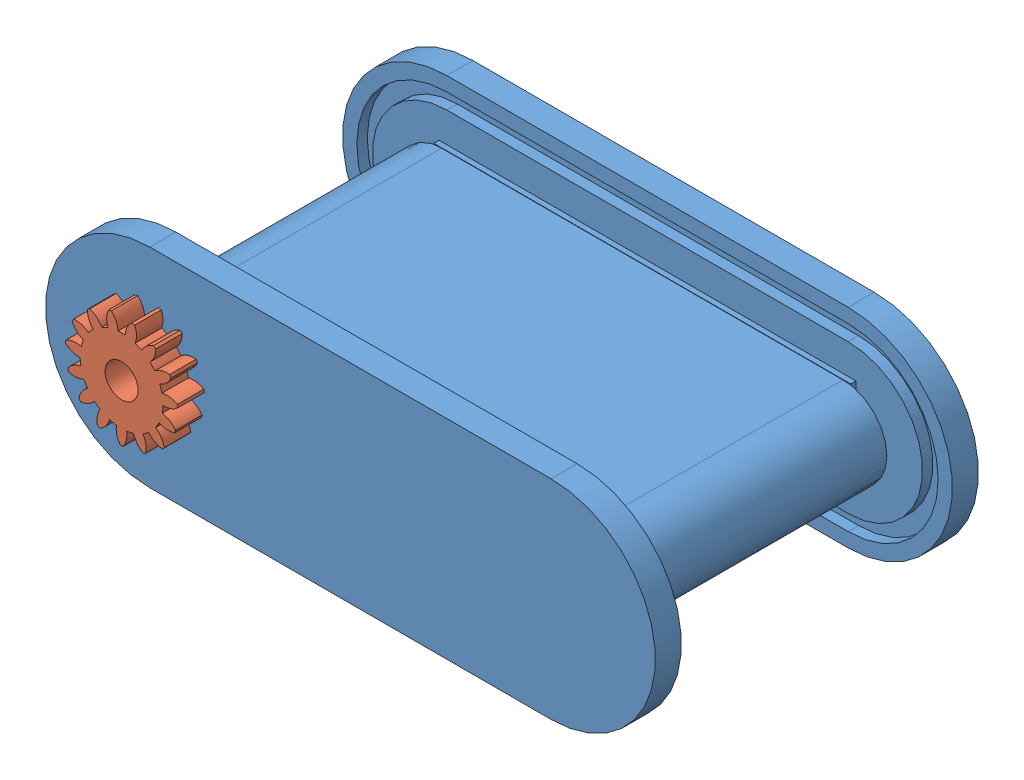
SolidWorks assembly Assembly, configuration Default. Lengths in mm.
Overall size (1170 400 670.8).
2 component instances, 2 part files, 1 mates.
Components (placement in the parent):
- SystemV0.1-1: SystemV0.1 [Default] at (-171.3514 15.3668 -253.8962) size (1170 400 620)
- Gear-1: Gear [Default] at (-426.928 15.2616 327.9144) x (0 0 -1) z (1 0 0) size (50.8 214.08 215.22)
Mates (geometry in assembly coordinates):
- Coincident1: coincident anti-aligned: plane of SystemV0.1-1 through (-416.3514 15.3668 316.1038) normal (0 0 1); plane of Gear-1 through (-419.6516 17.0792 316.1038) normal (0 0 -1)
